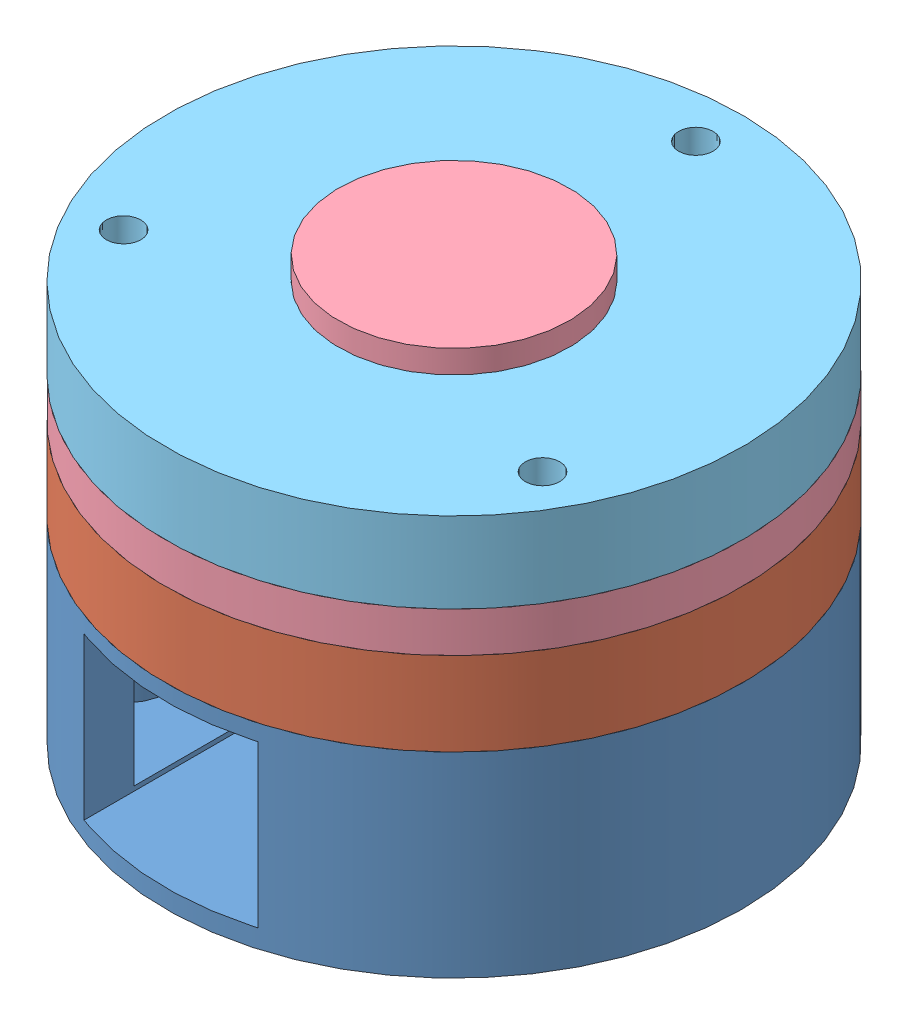
SolidWorks assembly Assem1, configuration Default. Lengths in mm.
Overall size (68.35 36.75 68.35).
5 component instances, 5 part files, 12 mates.
Components (placement in the parent):
- Bottom-2: Bottom [Default] at (7.2369 16.6416 49.2437) x (-1 0 0) z (0 -1 0) size (50 50 17)
- Ring-2: Ring [Default] at (7.2369 23.8916 49.2437) x (0.977355 0 -0.211606) z (0 -1 0) size (50 50 7.25)
- ground electrode-3: ground electrode [Default] at (7.2369 23.2916 49.2437) x (0.999366 0 -0.035617) z (0 1 0) size (42 41.6 1.6)
- Elastic part-2: Elastic part [Default] at (7.2369 27.3916 49.2437) x (0.864812 0 0.502097) z (0 1 0) size (50 50 12.5)
- Top part-1: Top part [Default] at (7.2369 27.3916 49.2437) x (-0.5 0 -0.866025) z (0 1 0) size (50 50 7)
Mates (geometry in assembly coordinates):
- Concentric7: concentric aligned: cylinder of Bottom-2 through (7.2369 16.6416 28.2437) axis (0 1 0) radius 1.5; cylinder of Ring-2 through (7.2369 23.8916 28.2437) axis (0 1 0) radius 1.5
- Concentric8: concentric aligned: cylinder of Bottom-2 through (25.4234 16.6416 59.7437) axis (0 1 0) radius 1.5; cylinder of Ring-2 through (25.4234 23.8916 59.7437) axis (0 1 0) radius 1.5
- Concentric11: concentric aligned: cylinder of Ring-2 through (25.4234 23.8916 59.7437) axis (0 1 0) radius 1.5; cylinder of Elastic part-2 through (25.4234 27.3916 59.7437) axis (0 1 0) radius 1.5
- Concentric12: concentric aligned: cylinder of Ring-2 through (7.2369 23.8916 28.2437) axis (0 1 0) radius 1.5; cylinder of Elastic part-2 through (7.2369 27.3916 28.2437) axis (0 1 0) radius 1.5
- Concentric13: concentric aligned: cylinder of Ring-2 through (-10.9496 23.8916 59.7437) axis (0 1 0) radius 1.5; cylinder of Elastic part-2 through (-10.9496 27.3916 59.7437) axis (0 1 0) radius 1.5
- Concentric14: concentric aligned: cylinder of ground electrode-3 through (7.2369 23.8916 49.2437) axis (0 1 0) radius 10; cylinder of Elastic part-2 through (7.2369 23.8916 49.2437) axis (0 1 0) radius 10
- Coincident9: coincident anti-aligned: plane of Ring-2 through (7.2369 16.6416 49.2437) normal (0 -1 0); plane of Bottom-2 through (7.2369 16.6416 49.2437) normal (0 1 0)
- Coincident10: coincident anti-aligned: plane of ground electrode-3 through (7.2369 23.8916 49.2437) normal (0 1 0); plane of Elastic part-2 through (7.2369 23.8916 49.2437) normal (0 -1 0)
- Coincident11: coincident anti-aligned: plane of Ring-2 through (7.2369 23.8916 49.2437) normal (0 1 0); plane of Elastic part-2 through (7.2369 23.8916 49.2437) normal (0 -1 0)
- Concentric15: concentric aligned: cylinder of Elastic part-2 through (7.2369 27.3916 28.2437) axis (0 1 0) radius 1.5; cylinder of Top part-1 through (7.2369 34.3916 28.2437) axis (0 1 0) radius 1.5
- Concentric16: concentric aligned: cylinder of Elastic part-2 through (25.4234 27.3916 59.7437) axis (0 1 0) radius 1.5; cylinder of Top part-1 through (25.4234 34.3916 59.7437) axis (0 1 0) radius 1.5
- Coincident12: coincident anti-aligned: plane of Elastic part-2 through (7.2369 27.3916 49.2437) normal (0 1 0); plane of Top part-1 through (7.2369 27.3916 49.2437) normal (0 -1 0)
